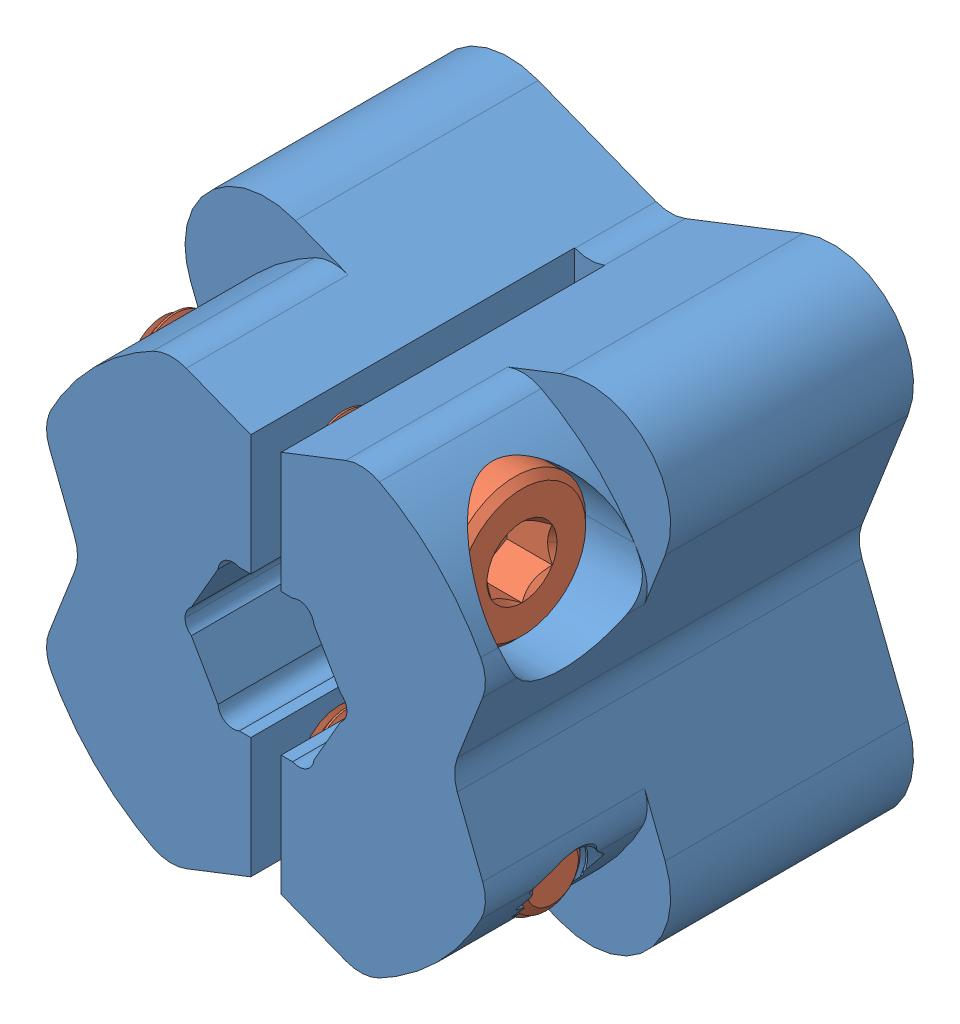
SolidWorks assembly 1310-0016-4008 assembly, configuration Default. Lengths in mm.
Overall size (24 24 22).
4 component instances, 2 part files, 0 mates.
Components (placement in the parent):
- 1310-0016-4008 assembly.STEP-1: 1310-0016-4008 assembly.STEP [Default] at origin size (24 24 22)
  - 1310-0016-4008.STEP-1: 1310-0016-4008.STEP [Default] at (-15.4211 -5.7247 3.0261) size (24 24 22)
  - 2800-0004-0014_90128A207.STEP-1: 2800-0004-0014_90128A207.STEP [Default] at (-25.1711 0.5753 18.6261) x (0 0 1) z (-1 0 0) size (7 7 18.01)
  - 2800-0004-0014_90128A207.STEP-2: 2800-0004-0014_90128A207.STEP [Default] at (-5.6711 -12.0247 18.6261) x (0 0 1) z (1 0 0) size (7 7 18.01)
